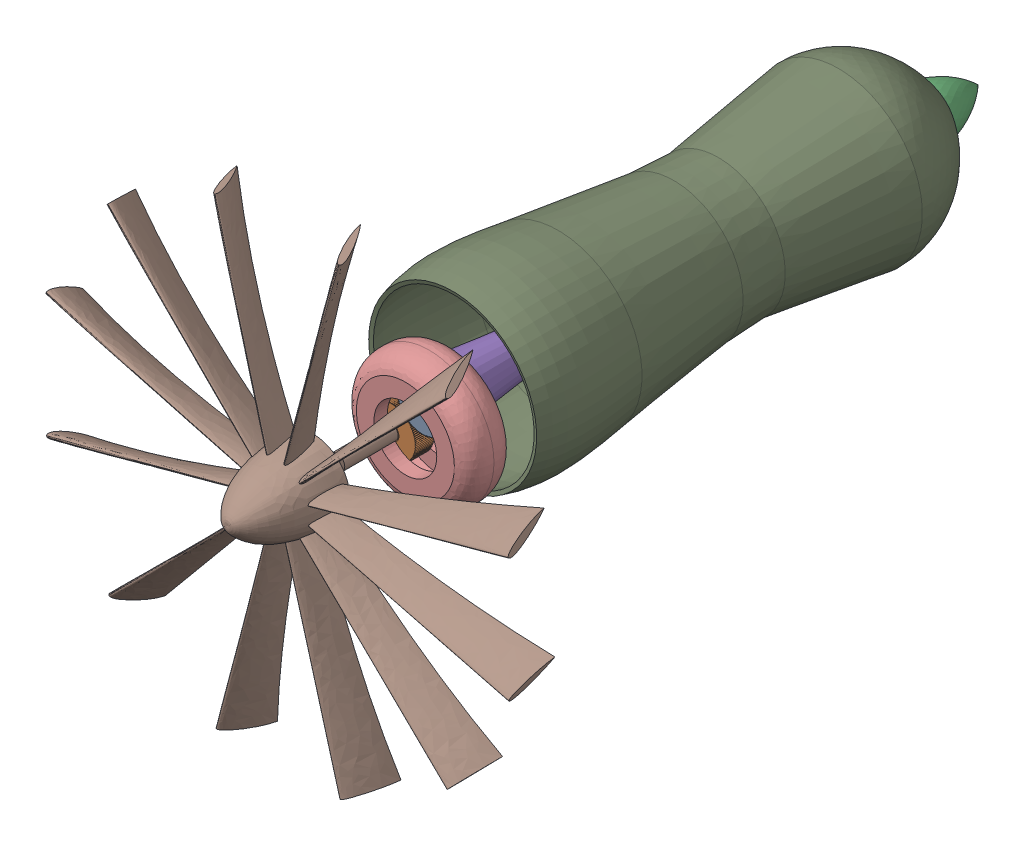
SolidWorks assembly TURBO-PROP ENGINE MINOR PROJECT, configuration Default. Lengths in mm.
Overall size (3077.64 3077.64 3854.18).
10 component instances, 9 part files, 11 mates.
Components (placement in the parent):
- 2-MINOR PROJECT [TURBOPROP]-GEARS-1: 2-MINOR PROJECT [TURBOPROP]-GEARS [Default] at (-41.4759 -236.8723 68.675) size (270.23 270.23 100)
- 2-MINOR PROJECT [TURBOPROP]-GEARS-2: 2-MINOR PROJECT [TURBOPROP]-GEARS [Default] at (-212.4114 -442.8276 68.675) size (270.23 270.23 100)
- 2-MINOR PROJECT [TURBOPROP]-MID SHAFT-1: 2-MINOR PROJECT [TURBOPROP]-MID SHAFT [Default] at (-180.2615 245.5418 1040.522) x (-0.848726 -0.528833 0) z (0 0 1) size (298.13 298.13 2974)
- 2-MINOR PROJECT [TURBOPROP]-COMPRESSORE-1: 2-MINOR PROJECT [TURBOPROP]-COMPRESSORE [Default] at (113.758 -187.9528 1217.5778) x (0.805167 0.593048 0) z (0 0 1) size (827.62 826.66 822.17)
- 2-MINOR PROJECT [TURBOPROP]-FRONT COVER-1: 2-MINOR PROJECT [TURBOPROP]-FRONT COVER [Default] at (-283.7869 -64.5075 846.8492) x (0.338995 -0.940788 0) z (0 0 1) size (280.02 280.02 644.88)
- 2-MINOR PROJECT [TURBOPROP]-MID COVER-1: 2-MINOR PROJECT [TURBOPROP]-MID COVER [Default] at (-287.1788 -44.8717 864.794) x (0.265551 -0.964097 0) z (0 0 1) size (327.39 327.39 464.9)
- 2-MINOR PROJECT [TURBOPROP]-TURBINE-1: 2-MINOR PROJECT [TURBOPROP]-TURBINE [Default] at (-140.6398 -217.6125 1214.2679) x (0.92445 -0.381304 0) z (0 0 1) size (663.35 663.35 370.97)
- 2-MINOR PROJECT [TURBOPROP]-PROPELLER-1: 2-MINOR PROJECT [TURBOPROP]-PROPELLER [Default] at (-212.4114 -183.1507 950.2319) x (-0.97356 0.228431 0) z (0 0 1) size (2560.45 2560.45 880.18)
- 2-MINOR PROJECT [TURBOPROP]-LAST COVER-1: 2-MINOR PROJECT [TURBOPROP]-LAST COVER [Default] at (20.1231 -226.1779 1276.176) x (0.970733 0.240162 0) z (0 0 1) size (982.46 982.46 2513.22)
- 2-MINOR PROJECT [TURBOPROP]-GEARS COVER-4: 2-MINOR PROJECT [TURBOPROP]-GEARS COVER [Default] at (-52.7992 -229.367 858.7006) size (695.01 695.01 253.61)
Mates (geometry in assembly coordinates):
- Coincident1: coincident aligned: plane of 2-MINOR PROJECT [TURBOPROP]-GEARS-1 through (-41.4759 22.8047 68.675) normal (0 0 1); plane of 2-MINOR PROJECT [TURBOPROP]-GEARS-2 through (-212.4114 -183.1507 68.675) normal (0 0 1)
- Lock1: lock: unknown of 2-MINOR PROJECT [TURBOPROP]-GEARS-1; unknown of 2-MINOR PROJECT [TURBOPROP]-GEARS-2
- Concentric1: concentric aligned: cylinder of 2-MINOR PROJECT [TURBOPROP]-GEARS-1 through (-41.4759 22.8047 -31.325) axis (0 0 1) radius 45.0165; cylinder of 2-MINOR PROJECT [TURBOPROP]-MID SHAFT-1 through (-41.4759 22.8047 -118.4097) axis (0 0 1) radius 34.8853
- Concentric2: concentric anti-aligned: cylinder of 2-MINOR PROJECT [TURBOPROP]-MID SHAFT-1 through (-41.4759 22.8047 -118.4097) axis (0 0 1) radius 34.8853; cylinder of 2-MINOR PROJECT [TURBOPROP]-COMPRESSORE-1 through (-41.4759 22.8047 -2713.4189) axis (0 0 -1) radius 43.5848
- Concentric3: concentric anti-aligned: cylinder of 2-MINOR PROJECT [TURBOPROP]-MID SHAFT-1 through (-41.4759 22.8047 -118.4097) axis (0 0 1) radius 34.8853; cone of 2-MINOR PROJECT [TURBOPROP]-FRONT COVER-1 through (-41.4759 22.8047 -107.3996) axis (0 0 -1)
- Concentric4: concentric anti-aligned: cylinder of 2-MINOR PROJECT [TURBOPROP]-MID SHAFT-1 through (-41.4759 22.8047 -118.4097) axis (0 0 1) radius 34.8853; cone of 2-MINOR PROJECT [TURBOPROP]-MID COVER-1 through (-41.4759 22.8047 -1569.0323) axis (0 0 -1)
- Concentric5: concentric anti-aligned: cylinder of 2-MINOR PROJECT [TURBOPROP]-MID SHAFT-1 through (-41.4759 22.8047 -118.4097) axis (0 0 1) radius 34.8853; cylinder of 2-MINOR PROJECT [TURBOPROP]-TURBINE-1 through (-41.4759 22.8047 -2782.22) axis (0 0 -1) radius 48.093
- Concentric6: concentric aligned: cylinder of 2-MINOR PROJECT [TURBOPROP]-GEARS-2 through (-212.4114 -183.1507 -31.325) axis (0 0 1) radius 45.0165; cylinder of 2-MINOR PROJECT [TURBOPROP]-PROPELLER-1 through (-212.4114 -183.1507 950.2319) axis (0 0 1) radius 40.7581
- Coincident5: coincident aligned: plane of 2-MINOR PROJECT [TURBOPROP]-GEARS-1 through (-41.4759 22.8047 68.675) normal (0 0 1); plane of 2-MINOR PROJECT [TURBOPROP]-MID SHAFT-1 through (-23.0274 -6.8034 68.675) normal (0 0 1)
- Coincident6: coincident aligned: plane of 2-MINOR PROJECT [TURBOPROP]-GEARS-2 through (-212.4114 -183.1507 68.675) normal (0 0 1); circle of 2-MINOR PROJECT [TURBOPROP]-PROPELLER-1
- Concentric21: concentric anti-aligned: cone of 2-MINOR PROJECT [TURBOPROP]-MID COVER-1 through (-41.4759 22.8047 -2033.9335) axis (0 0 1); cone of 2-MINOR PROJECT [TURBOPROP]-LAST COVER-1 through (-41.4759 22.8047 -657.5073) axis (0 0 -1)
